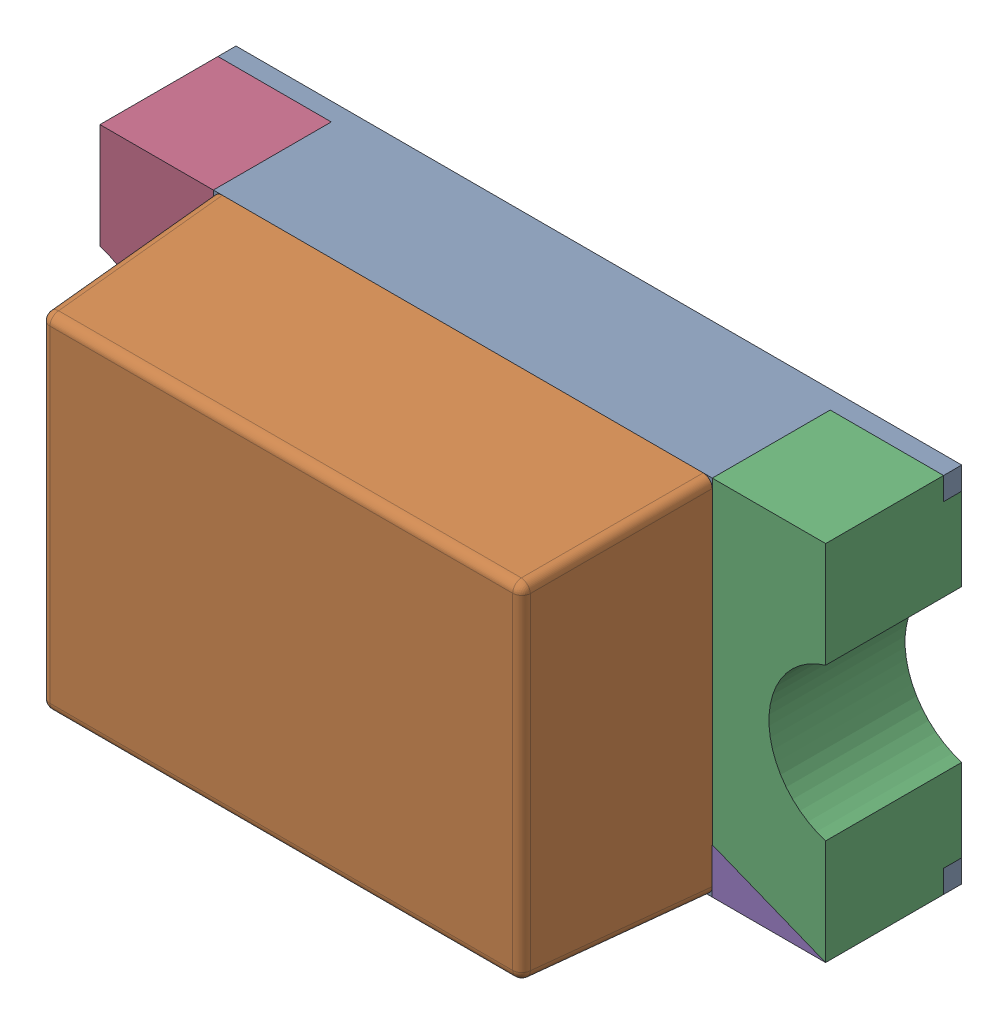
SolidWorks assembly LED200PCB, configuration Default. Lengths in mm.
Overall size (1.6 0.8 0.7).
6 component instances, 4 part files, 0 mates.
Components (placement in the parent):
- WL-SMCW_0603_LED-1: WL-SMCW_0603_LED [Default] at (80.1999 78.3999 0) x (-1 0 0) z (0 0 1) size (1.6 0.8 0.7)
  - housing-1: housing [Default] at origin size (1.6 0.8 0.3)
  - cover-1: cover [Default] at (0 0 0.3) size (1.1 0.8 0.4)
  - base-1: base [Default] at (-0.675 0 0) size (0.45 0.8 0.3)
  - base-2: base [Default] at (0.675 0 0) x (-1 0 0) z (0 0 1) size (0.45 0.8 0.3)
  - Polarity_Mark-1: Polarity_Mark [Default] at (-0.675 0.35 0.3) size (0.25 0.1 0)
